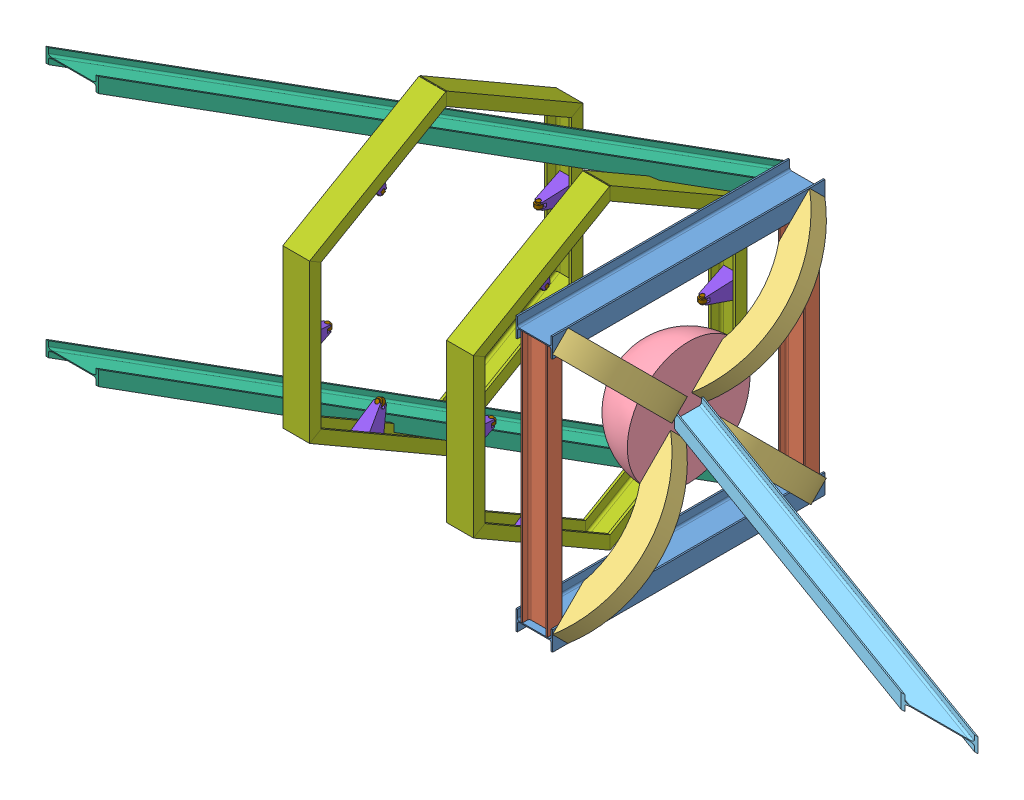
SolidWorks assembly Rocket test stand design Horizontal, configuration Default. Lengths in mm.
Overall size (3507.62 1176.93 1140.56).
33 component instances, 9 part files, 65 mates.
Components (placement in the parent):
- UB_CA-1: UB_CA [Default] at (452.2044 734.1423 330.412) x (0 -1 0) z (0 0 1) size (73 137 1016)
- UB_DC-1: UB_DC [Default] at (397.8009 -210.7577 1318.912) x (0 0 -1) z (0 1 0) size (55 98 943)
- UB_CA-2: UB_CA [Default] at (343.3973 -212.6577 330.412) x (0 1 0) z (0 0 1) size (73 137 1016)
- UB_DC-2: UB_DC [Default] at (397.8009 -210.7577 357.912) x (0 0 -1) z (0 1 0) size (55 98 943)
- curved beam_PC-1: curved beam_PC [Default] at (466.3009 742.0045 1317.7741) x (0 -0.707107 -0.707107) z (-1 0 0) size (622.3 81 123.51)
- load head-1: load head [Default] at (466.3009 272.2188 838.7864) x (0 0.999774 -0.021253) z (0 0.021253 0.999774) size (457.2 222.88 457.2)
- curved beam_PC-2: curved beam_PC [Default] at (466.3009 -220.5198 1317.7741) x (0 0.707107 -0.707107) z (-1 0 0) size (622.3 81 123.51)
- curved beam_PC-3: curved beam_PC [Default] at (466.3009 301.972 799.0823) x (0 0.707107 -0.707107) z (-1 0 0) size (622.3 81 123.51)
- UB_PE-1: UB_PE [Default] at (449.5419 272.2188 832.6866) x (0 1 0) z (0.939693 0 0.34202) size (55 98 1718.92)
- curved beam_PC-4: curved beam_PC [Default] at (466.3009 -220.5198 359.0498) x (0 0.707107 0.707107) z (-1 0 0) size (622.3 81 123.51)
- UB_GC-1: UB_GC [Default] at (353.8009 -212.6577 372.8472) x (0 -1 0) z (-0.866025 0 0.5) size (55 98 2026.92)
- UB_GC-2: UB_GC [Default] at (353.8009 734.1423 372.8472) x (0 -1 0) z (-0.866025 0 0.5) size (55 98 2026.92)
- mounting support-3: mounting support [Default] at (-490.9975 266.9195 836.2467) x (-0.000001 1 0) z (0 0 1) size (1176.93 100 510.17)
- mounting support part B-8: mounting support part B [Default] at (-522.6991 266.9195 1286.0747) x (0 1 0) z (-1 0 0) size (76.2 112.01 65)
- mounting support part C-6: mounting support part C [Default] at (-490.1991 279.6195 1230.0677) x (0 1 0) z (-1 0 0) size (25.4 25.4 25.4)
- mounting support-4: mounting support [Default] at (-489.4008 266.9195 836.2467) x (0 1 0) z (0 0 -1) size (1176.93 100 510.17)
- mounting support part B-9: mounting support part B [Default] at (-522.6988 -122.6429 1061.1607) x (-0.000001 0.5 0.866025) z (-1 -0.000001 -0.000001) size (76.2 112.01 65)
- mounting support part C-7: mounting support part C [Default] at (-490.1988 -67.7894 1044.1557) x (-0.000001 0.5 0.866025) z (-1 -0.000001 -0.000001) size (25.4 25.4 25.4)
- mounting support part B-10: mounting support part B [Default] at (-457.6993 656.482 1061.1607) x (0.000001 -0.5 0.866025) z (1 0.000001 0) size (76.2 112.01 65)
- mounting support part C-8: mounting support part C [Default] at (-490.1993 601.6285 1044.1557) x (0.000001 -0.5 0.866025) z (1 0.000001 0) size (25.4 25.4 25.4)
- mounting support part B-11: mounting support part B [Default] at (-457.6992 266.9196 386.4188) x (-0.000001 1 0) z (1 0.000001 0) size (76.2 112.01 65)
- mounting support part C-9: mounting support part C [Default] at (-490.1992 279.6196 442.4258) x (-0.000001 1 0) z (1 0.000001 0) size (25.4 25.4 25.4)
- Assem5^Rocket test stand design Horizontal-2: Assem5^Rocket test stand design Horizontal [Default] at (1926.5394 -223.2184 -736.6239) x (1 0 0) z (0 0 1) size (100 1176.93 1020.33) (virtual)
  - mounting support-1: mounting support [Default] at (-1806.3368 490.1382 1572.8709) x (-0.000001 1 0) z (0 0 1) size (1176.93 100 510.17)
  - mounting support part B-1: mounting support part B [Default] at (-1838.0384 490.1382 2022.6988) x (0 1 0) z (-1 0 0) size (76.2 112.01 65)
  - mounting support part C-1: mounting support part C [Default] at (-1805.5384 502.8382 1966.6918) x (0 1 0) z (-1 0 0) size (25.4 25.4 25.4)
  - mounting support-2: mounting support [Default] at (-1804.7401 490.1382 1572.8709) x (0 1 0) z (0 0 -1) size (1176.93 100 510.17)
  - mounting support part B-2: mounting support part B [Default] at (-1838.0381 100.5757 1797.7849) x (-0.000001 0.5 0.866025) z (-1 -0.000001 -0.000001) size (76.2 112.01 65)
  - mounting support part C-2: mounting support part C [Default] at (-1805.5382 155.4293 1780.7799) x (-0.000001 0.5 0.866025) z (-1 -0.000001 -0.000001) size (25.4 25.4 25.4)
  - mounting support part B-3: mounting support part B [Default] at (-1773.0386 879.7006 1797.7848) x (0.000001 -0.5 0.866025) z (1 0.000001 0) size (76.2 112.01 65)
  - mounting support part C-3: mounting support part C [Default] at (-1805.5386 824.8471 1780.7799) x (0.000001 -0.5 0.866025) z (1 0.000001 0) size (25.4 25.4 25.4)
  - mounting support part B-4: mounting support part B [Default] at (-1773.0386 490.1382 1123.043) x (-0.000001 1 0) z (1 0.000001 0) size (76.2 112.01 65)
  - mounting support part C-4: mounting support part C [Default] at (-1805.5386 502.8382 1179.05) x (-0.000001 1 0) z (1 0.000001 0) size (25.4 25.4 25.4)
Mates (geometry in assembly coordinates):
- Parallel2: parallel: line of UB_CA-1 through (466.3009 697.6423 1346.412) axis (0 0 -1)
- Parallel3: parallel anti-aligned: plane of UB_CA-1 through (453.7009 732.2423 1346.412) normal (0 -1 0)
- Coincident19: coincident aligned: plane of I channel 50 post-1 through (453.7009 725.2423 330.412) normal (0 0 -1); plane of UB_DC-2 through (442.1009 732.2423 330.412) normal (0 0 -1)
- Coincident23: coincident aligned: plane of I channel 50 post-1 through (453.7009 725.2423 1346.412) normal (0 0 1); plane of UB_DC-1 through (353.5009 732.2423 1346.412) normal (0 0 1)
- Coincident24: coincident anti-aligned: plane of UB_CA-1 through (453.7009 732.2423 1346.412) normal (0 -1 0); plane of UB_DC-2 through (360.5009 732.2423 349.112) normal (0 1 0)
- Distance1: distance = 19.5 mm aligned: plane of UB_CA-1 through (466.3009 770.6423 1346.412) normal (1 0 0); plane of UB_DC-2 through (446.8009 732.2423 330.412) normal (1 0 0)
- Distance2: distance = 19.5 mm aligned: plane of UB_DC-1 through (446.8009 732.2423 1291.412) normal (1 0 0); plane of UB_CA-1 through (466.3009 770.6423 1346.412) normal (1 0 0)
- Coincident27: coincident anti-aligned: plane of UB_CA-1 through (453.7009 732.2423 1346.412) normal (0 -1 0); plane of UB_DC-1 through (360.5009 732.2423 1310.112) normal (0 1 0)
- Coincident28: coincident anti-aligned: plane of UB_CA-2 through (341.9009 -210.7577 1346.412) normal (0 1 0); plane of UB_DC-2 through (360.5009 -210.7577 349.112) normal (0 -1 0)
- Coincident29: coincident aligned: plane of UB_CA-2 through (341.9009 -203.7577 330.412) normal (0 0 -1); plane of UB_DC-2 through (442.1009 732.2423 330.412) normal (0 0 -1)
- Distance3: distance = 19.5 mm aligned: plane of UB_DC-2 through (446.8009 732.2423 330.412) normal (1 0 0); plane of UB_CA-2 through (466.3009 -176.1577 1346.412) normal (1 0 0)
- Coincident31: coincident anti-aligned: plane of UB_CA-1 through (466.3009 770.6423 1346.412) normal (1 0 0); plane of curved beam_PC-3 through (466.3009 301.972 799.0823) normal (-1 0 0)
- Angle1: planar angle = 0.785398 rad anti-aligned: plane of UB_CA-1 through (466.3009 697.6423 1346.412) normal (0 -1 0); plane of curved beam_PC-3 through (466.3009 330.6098 827.7202) normal (0 0.707107 0.707107)
- Coincident33: coincident: line of UB_CA-1 through (466.3009 770.6423 1346.412) axis (0 0 -1); point of curved beam_PC-3
- Coincident34: coincident: line of UB_CA-1 through (466.3009 697.6423 330.412) axis (0 1 0); point of curved beam_PC-3
- Coincident35: coincident anti-aligned: plane of UB_CA-2 through (466.3009 -176.1577 1346.412) normal (1 0 0); plane of curved beam_PC-4 through (466.3009 -220.5198 359.0498) normal (-1 0 0)
- Angle2: planar angle = 0.785398 rad aligned: plane of curved beam_PC-4 through (466.3009 -77.3307 444.9633) normal (0 0.707107 -0.707107); plane of UB_CA-2 through (460.7009 -176.1577 1346.412) normal (0 1 0)
- Coincident37: coincident: line of UB_CA-2 through (466.3009 -249.1577 1346.412) axis (0 0 -1); point of curved beam_PC-4
- Coincident38: coincident: line of UB_CA-2 through (466.3009 -249.1577 330.412) axis (0 1 0); point of curved beam_PC-4
- Coincident39: coincident anti-aligned: plane of UB_CA-2 through (466.3009 -176.1577 1346.412) normal (1 0 0); plane of curved beam_PC-2 through (466.3009 -220.5198 1317.7741) normal (-1 0 0)
- Angle3: planar angle = 0.785398 rad anti-aligned: plane of curved beam_PC-2 through (466.3009 -134.6064 1174.585) normal (0 -0.707107 -0.707107); plane of UB_CA-2 through (460.7009 -176.1577 1346.412) normal (0 1 0)
- Coincident41: coincident: line of UB_CA-2 through (466.3009 -249.1577 1346.412) axis (0 0 -1); point of curved beam_PC-2
- Coincident42: coincident: line of UB_CA-2 through (466.3009 -249.1577 1346.412) axis (0 1 0); point of curved beam_PC-2
- Coincident43: coincident anti-aligned: plane of UB_CA-1 through (466.3009 770.6423 1346.412) normal (1 0 0); plane of curved beam_PC-1 through (466.3009 742.0045 1317.7741) normal (-1 0 0)
- Angle4: planar angle = 0.785398 rad anti-aligned: plane of curved beam_PC-1 through (466.3009 770.6423 1289.1363) normal (0 0.707107 -0.707107); plane of UB_CA-1 through (466.3009 697.6423 1346.412) normal (0 -1 0)
- Coincident45: coincident: line of UB_CA-1 through (466.3009 770.6423 1346.412) axis (0 0 -1); point of curved beam_PC-1
- Coincident46: coincident: line of UB_CA-1 through (466.3009 697.6423 1346.412) axis (0 1 0); point of curved beam_PC-1
- Coincident47: coincident anti-aligned: plane of curved beam_PC-1 through (466.3009 742.0045 1317.7741) normal (-1 0 0); plane of load head-1 through (466.3009 272.2188 838.7864) normal (1 0 0)
- Coincident50: coincident anti-aligned: plane of load head-1 through (466.3009 272.2188 838.7864) normal (1 0 0); plane of UB_PE-1 through (466.3009 272.2188 832.6866) normal (-1 0 0)
- Parallel5: parallel anti-aligned: plane of UB_CA-2 through (341.9009 -210.7577 1346.412) normal (0 1 0); plane of UB_PE-1 through (2084.5381 270.4188 1388.0827) normal (0 -1 0)
- Coincident52: coincident: point of load head-1; point of UB_PE-1
- Coincident53: coincident anti-aligned: plane of UB_CA-2 through (329.3009 -249.1577 1346.412) normal (-1 0 0); plane of UB_GC-1 through (329.3009 -212.6577 372.8472) normal (1 0 0)
- Coincident55: coincident: plane of UB_CA-2 through (341.9009 -203.7577 330.412) normal (0 0 -1); line of UB_GC-1 through (329.3009 -185.1577 330.412) axis (0 -1 0)
- Coincident57: coincident anti-aligned: plane of UB_CA-1 through (329.3009 697.6423 1346.412) normal (-1 0 0); plane of UB_GC-2 through (329.3009 734.1423 372.8472) normal (1 0 0)
- Coincident59: coincident: plane of UB_CA-1 through (453.7009 725.2423 330.412) normal (0 0 -1); line of UB_GC-2 through (329.3009 761.6423 330.412) axis (0 -1 0)
- Coincident60: coincident: moEndPointRef_w of UB_CA-1; unknown of UB_GC-2
- Coincident61: coincident: unknown of UB_CA-2; unknown of UB_GC-1
- Distance4: distance = 508 mm: line of UB_DC-1 through (446.8009 732.2423 1346.412) axis (0 -1 0)
- Distance8: distance = 177.8 mm: line of UB_DC-1 through (348.8009 732.2423 1346.412) axis (0 -1 0); line of Assem5^Rocket test stand design Horizontal-2/mounting support-1 through (171.0009 -27.6242 1346.412) axis (0 1 0)
- Coincident132: coincident aligned: plane of UB_DC-1 through (353.5009 732.2423 1346.412) normal (0 0 1); plane of Assem5^Rocket test stand design Horizontal-2/mounting support-1 through (71.0009 -27.8242 1346.412) normal (0 0 1)
- Coincident86: coincident anti-aligned: line of mounting support-3 through (-540.1995 853.5074 836.2467) axis (1 0.000001 0); line of mounting support-4 through (-440.1995 853.5074 836.2468) axis (-1 -0.000001 0)
- Coincident92: coincident: point of mounting support-3; line of mounting support-4 through (-540.1995 806.0074 836.2467) axis (0 1 0)
- Coincident110: coincident anti-aligned: plane of mounting support-3 through (-457.6991 -25.3244 1342.0817) normal (0 0 -1); plane of mounting support part B-8 through (-457.6991 305.0195 1342.0817) normal (0 0 1)
- Coincident111: coincident aligned: line of mounting support-3 through (-457.6991 -25.1244 1342.0817) axis (0 1 0); line of mounting support part B-8 through (-457.6991 228.8195 1342.0817) axis (0 1 0)
- Coincident112: coincident: unknown of mounting support-3; unknown of mounting support part B-8
- Coincident114: coincident anti-aligned: plane of mounting support-3 through (-457.6984 -317.1683 836.2467) normal (-0.000001 0.866025 -0.5); plane of mounting support part B-9 through (-457.6988 -152.0963 1122.1598) normal (0.000001 -0.866025 0.5)
- Coincident115: coincident aligned: line of mounting support-3 through (-522.6984 -317.1684 836.2467) axis (-0.000001 0.5 0.866025); line of mounting support part B-9 through (-522.6987 -190.1964 1056.1686) axis (-0.000001 0.5 0.866025)
- Coincident116: coincident: unknown of mounting support part B-9; unknown of mounting support-3
- Coincident118: coincident anti-aligned: plane of mounting support-3 through (-457.6991 558.9635 1342.0817) normal (0 -0.866025 -0.5); plane of mounting support part B-10 through (-522.6993 685.9354 1122.1598) normal (0 0.866025 0.5)
- Coincident120: coincident anti-aligned: line of mounting support-3 through (-522.6991 558.9635 1342.0817) axis (-0.000001 0.5 -0.866025); line of mounting support part B-10 through (-522.6993 724.0354 1056.1686) axis (0.000001 -0.5 0.866025)
- Concentric1: concentric aligned: cylinder of mounting support part B-8 through (-490.1991 228.8195 1230.0677) axis (0 1 0) radius 7.62; cylinder of mounting support part C-6 through (-490.1991 254.2195 1230.0677) axis (0 1 0) radius 7.62
- Coincident78: coincident: point of mounting support part B-8; plane of mounting support part C-6 through (-490.1991 254.2195 1230.0677) normal (0 -1 0)
- Coincident122: coincident anti-aligned: plane of mounting support-4 through (-522.6988 -25.3245 330.4118) normal (0 0 1); plane of mounting support part B-11 through (-522.6992 305.0195 330.4118) normal (0 0 -1)
- Coincident123: coincident aligned: line of mounting support-4 through (-522.6988 -25.1244 330.4118) axis (-0.000001 1 0); line of mounting support part B-11 through (-522.6991 228.8195 330.4118) axis (-0.000001 1 0)
- Coincident124: coincident: unknown of mounting support-4; unknown of mounting support part B-11
- Concentric2: concentric aligned: cylinder of mounting support part B-9 through (-490.1988 -93.1894 1000.1617) axis (-0.000001 0.5 0.866025) radius 7.62; cylinder of mounting support part C-7 through (-490.1988 -80.4894 1022.1587) axis (-0.000001 0.5 0.866025) radius 7.62
- Coincident113: coincident: point of mounting support part B-9; plane of mounting support part C-7 through (-490.1988 -80.4894 1022.1587) normal (0.000001 -0.5 -0.866025)
- Concentric3: concentric aligned: cylinder of mounting support part B-10 through (-490.1993 627.0285 1000.1616) axis (0.000001 -0.5 0.866025) radius 7.62; cylinder of mounting support part C-8 through (-490.1993 614.3285 1022.1587) axis (0.000001 -0.5 0.866025) radius 7.62
- Coincident117: coincident: point of mounting support part B-10; plane of mounting support part C-8 through (-490.1993 614.3285 1022.1587) normal (-0.000001 0.5 -0.866025)
- Concentric4: concentric aligned: cylinder of mounting support part B-11 through (-490.1991 228.8196 442.4258) axis (-0.000001 1 0) radius 7.62; cylinder of mounting support part C-9 through (-490.1992 254.2196 442.4258) axis (-0.000001 1 0) radius 7.62
- Coincident121: coincident: point of mounting support part B-11; plane of mounting support part C-9 through (-490.1992 254.2196 442.4258) normal (0.000001 -1 0)
- Parallel32: parallel aligned: plane of UB_DC-1 through (353.5009 732.2423 1346.412) normal (0 0 1); plane of mounting support-3 through (-540.1991 -27.8244 1346.4118) normal (0 0 1)
- Parallel33: parallel anti-aligned: line of UB_DC-1 through (348.8009 732.2423 1346.412) axis (0 -1 0); line of mounting support-3 through (-490.9976 -26.3744 1344.2467) axis (0 1 0)
- Distance9: distance = 711.2 mm: line of mounting support-3 through (-540.1991 -27.6244 1346.4118) axis (0 1 0); line of Assem5^Rocket test stand design Horizontal-2/mounting support-1 through (171.0009 -27.6242 1346.412) axis (0 1 0)
- Coincident133: coincident aligned: line of mounting support-4 through (-440.1991 -322.1683 836.2468) axis (-1 0 0); line of Assem5^Rocket test stand design Horizontal-2/mounting support-2 through (171.0009 -322.1681 836.2469) axis (-1 0 0)
